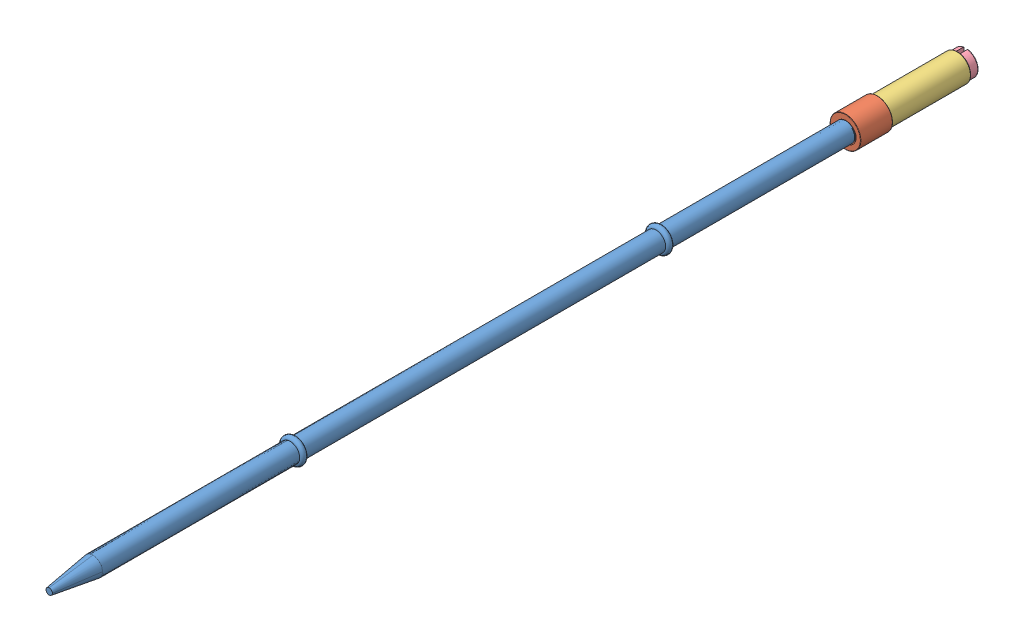
SolidWorks assembly LGGC, configuration Default. Lengths in mm.
Overall size (26.01 26.01 572.78).
4 component instances, 4 part files, 3 mates.
Components (placement in the parent):
- Light gas gun cartridge-1: Light gas gun cartridge [Default] at (121.2795 272.5515 168.1817) size (15.73 15.73 508.68)
- Second part of LGCC-1: Second part of LGCC [Default] at (121.6434 272.1606 158.8637) x (0.483637 -0.875269 0) z (0 0 1) size (19.14 19.14 21.17)
- Third part of LGCC-1: Third part of LGCC [Default] at (121.2795 272.5515 158.8196) x (-0.999607 0.028045 0) z (0 0 -1) size (17 17 61.2)
- Fourth part of LGGC-1: Fourth part of LGGC [Default] at (121.2795 272.5515 108.3995) size (15.5 15.35 22)
Mates (geometry in assembly coordinates):
- Concentric1: concentric: cylinder of Light gas gun cartridge-1 through (121.2795 272.5515 676.1817) axis (0 0 -1) radius 6; cylinder of Second part of LGCC-1 through (121.2795 272.5515 178.8637) axis (0 0 -1) radius 9.5719
- Concentric2: concentric: cylinder of Second part of LGCC-1 through (121.2795 272.5515 178.8637) axis (0 0 -1) radius 9.5719; cylinder of Third part of LGCC-1 through (121.2795 272.5515 108.8196) axis (0 0 1) radius 8.5
- Concentric3: concentric: cylinder of Third part of LGCC-1 through (121.2795 272.5515 108.8196) axis (0 0 1) radius 8.5; cylinder of Fourth part of LGGC-1 through (121.2795 272.5515 103.3995) axis (0 0 1) radius 7.75
